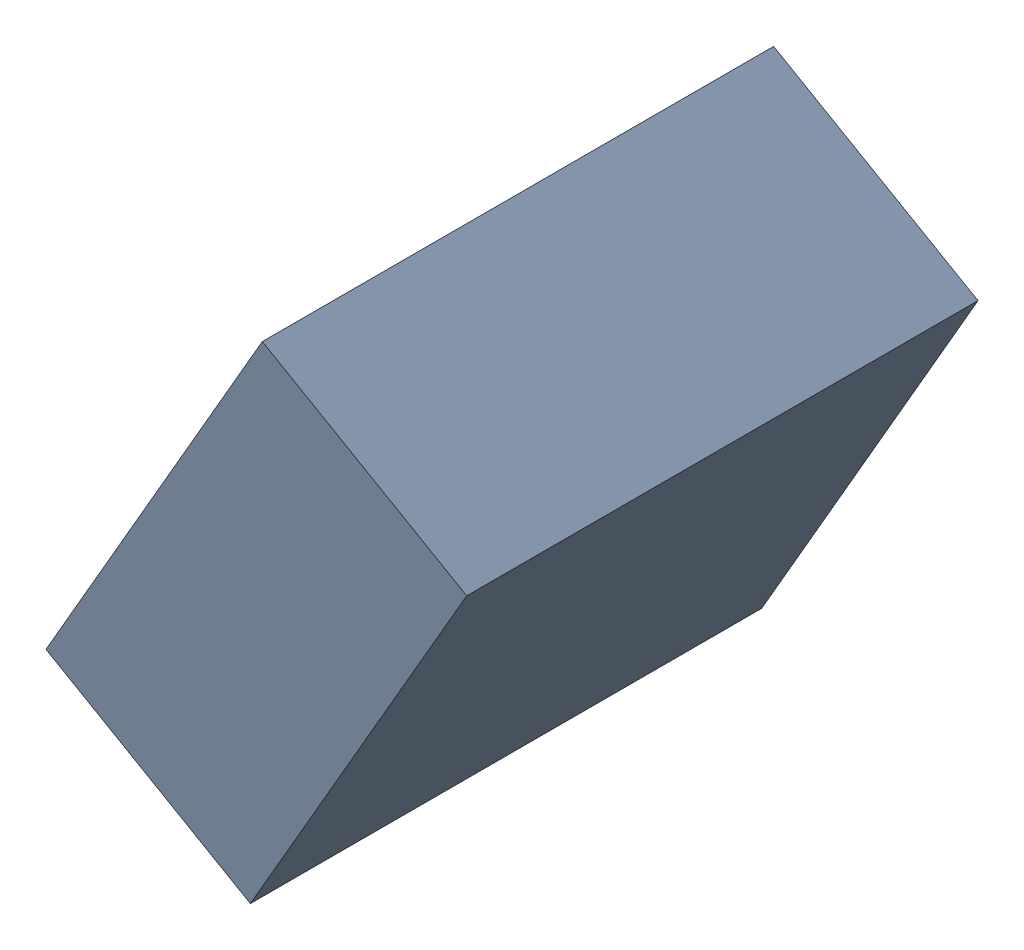
SolidWorks assembly C26_TDA3, configuration Standard. Lengths in mm.
Overall size (1.07 1.25 1.3).
2 component instances, 1 part files, 0 mates.
Components (placement in the parent):
- 885543328-1: 885543328 [Standard] at (33.4421 -21.7679 0) size (1.07 1.25 1.3)
  - Extruded_26-1: Extruded_26 [Standard] at origin size (1.07 1.25 1.3)
